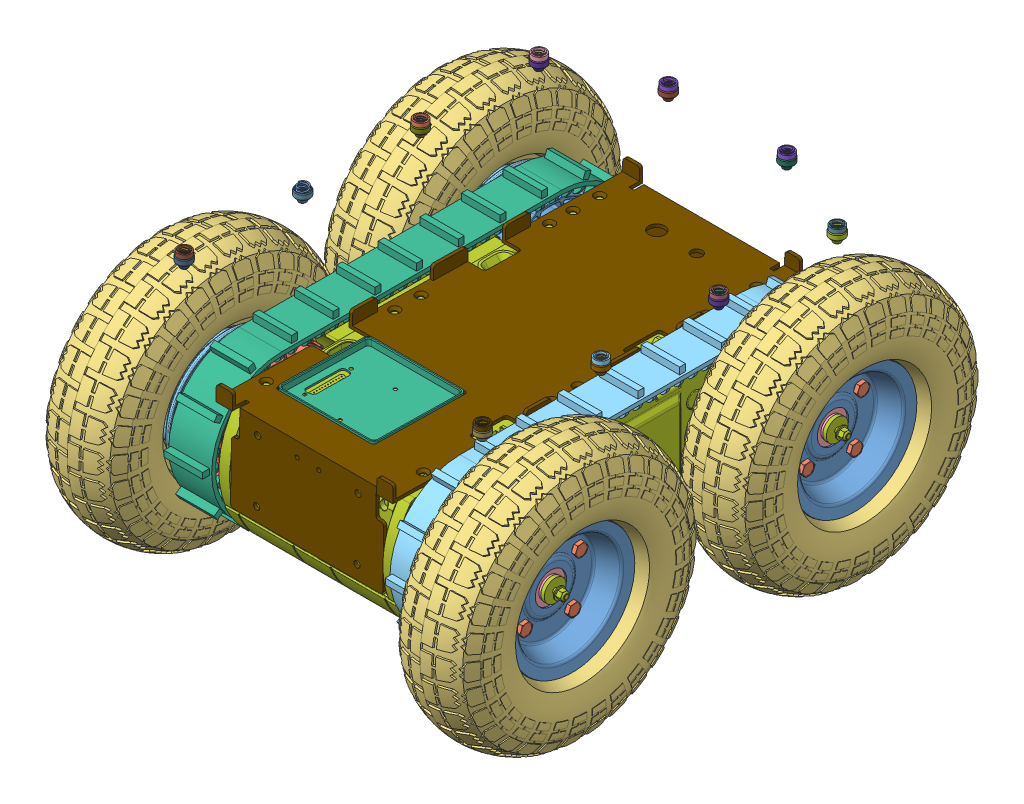
SolidWorks assembly RD_Payload_Rev_A, configuration Default. Lengths in mm.
Overall size (444.69 367.29 650.79).
94 component instances, 59 part files, 0 mates.
Components (placement in the parent):
- RD_Payload_Rev_A.step-1: RD_Payload_Rev_A.step [Default] at origin size (444.69 371.55 650.79)
  - 10 in Wheel.step-1: 10 in Wheel.step [Default] at (178.555 0 0) x (0 -0.59872 0.800958) z (-1 0 0) size (260.79 263.33 83.58)
    - Hub Outer.step-1: Hub Outer.step [Default] x (1 0 0) z (0 0 -1) size (127 127 25.4)
    - Bolt M8x14mm.step-1: Bolt M8x14mm.step [Default] at (0 34.925 -7.0104) x (1 0 0) z (0 -1 0) size (11.71 18.58 13.52)
    - Bolt M8x14mm.step-2: Bolt M8x14mm.step [Default] at (-34.925 0 -7.0104) x (1 0 0) z (0 -1 0) size (11.71 18.58 13.52)
    - Bolt M8x14mm.step-3: Bolt M8x14mm.step [Default] at (0 -34.925 -7.0104) x (1 0 0) z (0 -1 0) size (11.71 18.58 13.52)
    - Bolt M8x14mm.step-4: Bolt M8x14mm.step [Default] at (34.925 0 -7.0104) x (1 0 0) z (0 -1 0) size (11.71 18.58 13.52)
    - Tire.step-1: Tire.step [Default] x (0 0 -1) z (-0.99993 -0.011854 0) size (83.58 260.3 257.72)
    - Bearing.step-1: Bearing.step [Default] at (0 0 -2.159) x (0.59872 -0.800958 0) z (0 0 -1) size (37.59 37.59 12.4)
    - ModifiedWheelHub.step-1: ModifiedWheelHub.step [Default] at (-0.127 0 22.847) x (0 0 -1) z (1 0 0) size (30.5 125 125)
  - 10 in Wheel_1.step-1: 10 in Wheel_1.step [Default] at (180.555 0 -283.5) x (0 -0.59872 0.800958) z (-1 0 0) size (260.79 263.33 83.58)
    - Hub Outer.step-1: Hub Outer.step [Default] x (1 0 0) z (0 0 -1) size (127 127 25.4)
    - Bolt M8x14mm.step-1: Bolt M8x14mm.step [Default] at (0 34.925 -7.0104) x (1 0 0) z (0 -1 0) size (11.71 18.58 13.52)
    - Bolt M8x14mm.step-2: Bolt M8x14mm.step [Default] at (-34.925 0 -7.0104) x (1 0 0) z (0 -1 0) size (11.71 18.58 13.52)
    - Bolt M8x14mm.step-3: Bolt M8x14mm.step [Default] at (0 -34.925 -7.0104) x (1 0 0) z (0 -1 0) size (11.71 18.58 13.52)
    - Bolt M8x14mm.step-4: Bolt M8x14mm.step [Default] at (34.925 0 -7.0104) x (1 0 0) z (0 -1 0) size (11.71 18.58 13.52)
    - Tire.step-1: Tire.step [Default] x (0 0 -1) z (-0.99993 -0.011854 0) size (83.58 260.3 257.72)
    - Bearing.step-1: Bearing.step [Default] at (0 0 -2.159) x (0.59872 -0.800958 0) z (0 0 -1) size (37.59 37.59 12.4)
    - ModifiedWheelHub.step-1: ModifiedWheelHub.step [Default] at (-0.127 0 22.847) x (0 0 -1) z (1 0 0) size (30.5 125 125)
  - 10 in Wheel_2.step-1: 10 in Wheel_2.step [Default] at (-180.555 0 -283.5) x (0 -0.800958 0.59872) z (1 0 0) size (260.79 263.33 83.58)
    - Hub Outer.step-1: Hub Outer.step [Default] x (1 0 0) z (0 0 -1) size (127 127 25.4)
    - Bolt M8x14mm.step-1: Bolt M8x14mm.step [Default] at (0 34.925 -7.0104) x (1 0 0) z (0 -1 0) size (11.71 18.58 13.52)
    - Bolt M8x14mm.step-2: Bolt M8x14mm.step [Default] at (-34.925 0 -7.0104) x (1 0 0) z (0 -1 0) size (11.71 18.58 13.52)
    - Bolt M8x14mm.step-3: Bolt M8x14mm.step [Default] at (0 -34.925 -7.0104) x (1 0 0) z (0 -1 0) size (11.71 18.58 13.52)
    - Bolt M8x14mm.step-4: Bolt M8x14mm.step [Default] at (34.925 0 -7.0104) x (1 0 0) z (0 -1 0) size (11.71 18.58 13.52)
    - Tire.step-1: Tire.step [Default] x (0 0 -1) z (-0.99993 -0.011854 0) size (83.58 260.3 257.72)
    - Bearing.step-1: Bearing.step [Default] at (0 0 -2.159) x (0.59872 -0.800958 0) z (0 0 -1) size (37.59 37.59 12.4)
    - ModifiedWheelHub.step-1: ModifiedWheelHub.step [Default] at (-0.127 0 22.847) x (0 0 -1) z (1 0 0) size (30.5 125 125)
  - 10 in Wheel_3.step-1: 10 in Wheel_3.step [Default] at (-178.555 0 0) x (0 -0.800958 0.59872) z (1 0 0) size (260.79 263.33 83.58)
    - Hub Outer.step-1: Hub Outer.step [Default] x (1 0 0) z (0 0 -1) size (127 127 25.4)
    - Bolt M8x14mm.step-1: Bolt M8x14mm.step [Default] at (0 34.925 -7.0104) x (1 0 0) z (0 -1 0) size (11.71 18.58 13.52)
    - Bolt M8x14mm.step-2: Bolt M8x14mm.step [Default] at (-34.925 0 -7.0104) x (1 0 0) z (0 -1 0) size (11.71 18.58 13.52)
    - Bolt M8x14mm.step-3: Bolt M8x14mm.step [Default] at (0 -34.925 -7.0104) x (1 0 0) z (0 -1 0) size (11.71 18.58 13.52)
    - Bolt M8x14mm.step-4: Bolt M8x14mm.step [Default] at (34.925 0 -7.0104) x (1 0 0) z (0 -1 0) size (11.71 18.58 13.52)
    - Tire.step-1: Tire.step [Default] x (0 0 -1) z (-0.99993 -0.011854 0) size (83.58 260.3 257.72)
    - Bearing.step-1: Bearing.step [Default] at (0 0 -2.159) x (0.59872 -0.800958 0) z (0 0 -1) size (37.59 37.59 12.4)
    - ModifiedWheelHub.step-1: ModifiedWheelHub.step [Default] at (-0.127 0 22.847) x (0 0 -1) z (1 0 0) size (30.5 125 125)
  - R&D Payload.step-1: R&D Payload.step [Default] at (7.0458 -116.5686 -486.2193) x (1 0 0) z (0 0.999848 -0.017452) size (435.85 572.37 235.56)
    - R&D Payload Assembly (approx, don't use) v9.step-1: R&D Payload Assembly (approx, don't use) v9.step [Default] at (0 0 150) size (435.85 572.37 129.48)
      - PPatrol Payload v6.step-1: PPatrol Payload v6.step [Default] at (200.9785 -625.114 143.2331) x (0 -1 0) z (-1 0 0) size (572.37 31.75 435.85)
        - 8020-1010-BLACK-1010-BLACK X 72 v1.step-1: 8020-1010-BLACK-1010-BLACK X 72 v1.step [Default] at (-12.6721 -12.7 413.3053) size (25.4 25.4 387.35) (hidden)
        - 8020-1010-BLACK-1010-BLACK X 72 v1 (1).step-1: 8020-1010-BLACK-1010-BLACK X 72 v1 (1).step [Default] at (-25.3721 -12.7 400.6053) x (0 0 -1) z (1 0 0) size (25.4 25.4 523.88) (hidden)
        - 8020-1010-BLACK-1010-BLACK X 72 v1 (2).step-1: 8020-1010-BLACK-1010-BLACK X 72 v1 (2).step [Default] at (-536.5471 -12.7 387.9053) size (25.4 25.4 387.35) (hidden)
        - 8020-1010-BLACK-1010-BLACK X 72 v1 (1) (1).step-1: 8020-1010-BLACK-1010-BLACK X 72 v1 (1) (1).step [Default] at (-637.3851 -12.7 -418.5447) x (0 0 1) z (-1 0 0) size (25.4 25.4 523.88) (hidden)
        - Polycarbonate.step-1: Polycarbonate.step [Default] at origin size (572.37 6.4 435.85) (hidden)
      - Gasket (approximate).step-1: Gasket (approximate).step [Default] at (-17.1019 -288.0369 37.8723) x (1 0 0) z (0 -1 0) size (325.94 3 463.22) (hidden)
      - Component8.step-1: Component8.step [Default] at (-17.1019 -288.0369 37.8723) x (1 0 0) z (0 -1 0) size (99.02 8.47 93.56)
      - Component9.step-1: Component9.step [Default] at (-17.1019 -288.0369 37.8723) x (1 0 0) z (0 -1 0) size (13.43 10.76 13.43) (hidden)
      - Component10.step-1: Component10.step [Default] at (-17.1019 -288.0369 37.8723) x (1 0 0) z (0 -1 0) size (10.99 7.47 11.04)
      - Component11.step-1: Component11.step [Default] at (-17.1019 -288.0369 37.8723) x (1 0 0) z (0 -1 0) size (10.99 7.47 11.04) (hidden)
      - Component12.step-1: Component12.step [Default] at (-17.1019 -288.0369 37.8723) x (1 0 0) z (0 -1 0) size (325.94 88.29 30) (hidden)
      - Component13.step-1: Component13.step [Default] at (-17.1019 -288.0369 37.8723) x (1 0 0) z (0 -1 0) size (13.43 10.76 13.43)
      - Component14.step-1: Component14.step [Default] at (-17.1019 -288.0369 37.8723) x (1 0 0) z (0 -1 0) size (10.99 7.47 11.04)
      - Component15.step-1: Component15.step [Default] at (-17.1019 -288.0369 37.8723) x (1 0 0) z (0 -1 0) size (14.52 10.94 14.52)
      - Component16.step-1: Component16.step [Default] at (-17.1019 -288.0369 37.8723) x (1 0 0) z (0 -1 0) size (13.43 10.76 13.43)
      - Component17.step-1: Component17.step [Default] at (-17.1019 -288.0369 37.8723) x (1 0 0) z (0 -1 0) size (10.99 7.47 11.04) (hidden)
      - Component18.step-1: Component18.step [Default] at (-17.1019 -288.0369 37.8723) x (1 0 0) z (0 -1 0) size (14.52 10.94 14.52) (hidden)
      - Component19.step-1: Component19.step [Default] at (-17.1019 -288.0369 37.8723) x (1 0 0) z (0 -1 0) size (13.43 10.76 13.43) (hidden)
      - Component20.step-1: Component20.step [Default] at (-17.1019 -288.0369 37.8723) x (1 0 0) z (0 -1 0) size (10.99 7.47 11.04)
      - Component21.step-1: Component21.step [Default] at (-17.1019 -288.0369 37.8723) x (1 0 0) z (0 -1 0) size (10.99 7.47 11.04)
      - Component22.step-1: Component22.step [Default] at (-17.1019 -288.0369 37.8723) x (1 0 0) z (0 -1 0) size (14.52 10.94 14.52) (hidden)
      - Component23.step-1: Component23.step [Default] at (-17.1019 -288.0369 37.8723) x (1 0 0) z (0 -1 0) size (14.52 10.94 14.52)
      - Component24.step-1: Component24.step [Default] at (-17.1019 -288.0369 37.8723) x (1 0 0) z (0 -1 0) size (10.99 7.47 11.04)
      - Component25.step-1: Component25.step [Default] at (-17.1019 -288.0369 37.8723) x (1 0 0) z (0 -1 0) size (13.43 10.76 13.43) (hidden)
      - Component26.step-1: Component26.step [Default] at (-17.1019 -288.0369 37.8723) x (1 0 0) z (0 -1 0) size (14.52 10.94 14.52)
      - Component27.step-1: Component27.step [Default] at (-17.1019 -288.0369 37.8723) x (1 0 0) z (0 -1 0) size (14.52 10.94 14.52)
      - Component28.step-1: Component28.step [Default] at (-17.1019 -288.0369 37.8723) x (1 0 0) z (0 -1 0) size (13.43 10.76 13.43)
      - Component29.step-1: Component29.step [Default] at (-17.1019 -288.0369 37.8723) x (1 0 0) z (0 -1 0) size (10.99 7.47 11.04)
      - Component30.step-1: Component30.step [Default] at (-17.1019 -288.0369 37.8723) x (1 0 0) z (0 -1 0) size (13.43 10.76 13.43)
      - Component31.step-1: Component31.step [Default] at (-17.1019 -288.0369 37.8723) x (1 0 0) z (0 -1 0) size (10.99 7.47 11.04)
      - Component32.step-1: Component32.step [Default] at (-17.1019 -288.0369 37.8723) x (1 0 0) z (0 -1 0) size (13.43 10.76 13.43)
      - Component33.step-1: Component33.step [Default] at (-17.1019 -288.0369 37.8723) x (1 0 0) z (0 -1 0) size (13.43 10.76 13.43)
      - Component34.step-1: Component34.step [Default] at (-17.1019 -288.0369 37.8723) x (1 0 0) z (0 -1 0) size (10.99 7.47 11.04)
      - Component35.step-1: Component35.step [Default] at (-17.1019 -288.0369 37.8723) x (1 0 0) z (0 -1 0) size (325.94 88.29 403.22) (hidden)
      - Component36.step-1: Component36.step [Default] at (-17.1019 -288.0369 37.8723) x (1 0 0) z (0 -1 0) size (325.94 88.29 30) (hidden)
      - Component37.step-1: Component37.step [Default] at (-17.1019 -288.0369 37.8723) x (1 0 0) z (0 -1 0) size (14.52 10.94 14.52)
      - Component38.step-1: Component38.step [Default] at (-17.1019 -288.0369 37.8723) x (1 0 0) z (0 -1 0) size (13.43 10.76 13.43)
      - Component39.step-1: Component39.step [Default] at (-17.1019 -288.0369 37.8723) x (1 0 0) z (0 -1 0) size (14.52 10.94 14.52)
      - Component40.step-1: Component40.step [Default] at (-17.1019 -288.0369 37.8723) x (1 0 0) z (0 -1 0) size (10.99 7.47 11.04)
      - Component41.step-1: Component41.step [Default] at (-17.1019 -288.0369 37.8723) x (1 0 0) z (0 -1 0) size (14.52 10.94 14.52)
      - Component42.step-1: Component42.step [Default] at (-17.1019 -288.0369 37.8723) x (1 0 0) z (0 -1 0) size (14.52 10.94 14.52)
      - Component43.step-1: Component43.step [Default] at (-17.1019 -288.0369 37.8723) x (1 0 0) z (0 -1 0) size (13.43 10.76 13.43)
      - Component44.step-1: Component44.step [Default] at (-17.1019 -288.0369 37.8723) x (1 0 0) z (0 -1 0) size (13.43 10.76 13.43)
      - Component45.step-1: Component45.step [Default] at (-17.1019 -288.0369 37.8723) x (1 0 0) z (0 -1 0) size (14.52 10.94 14.52)
      - Component46.step-1: Component46.step [Default] at (-17.1019 -288.0369 37.8723) x (1 0 0) z (0 -1 0) size (10.99 7.47 11.04)
      - Component47.step-1: Component47.step [Default] at (-17.1019 -288.0369 37.8723) x (1 0 0) z (0 -1 0) size (14.52 10.94 14.52)
    - Rear Bracket and Payload Spacer (XXXXXX) v2.step-1: Rear Bracket and Payload Spacer (XXXXXX) v2.step [Default] at (-7.0458 -148.6279 107.7511) x (-1 0 0) z (0 1 0) size (179.03 126.19 414.77)
  - 100251_revA.step-1: 100251_revA.step [Default] at (-101.5 0 -283.5) x (0 0.000178 1) z (-1 0 0) size (137.55 138 25)
  - 100251_revA (1).step-1: 100251_revA (1).step [Default] at (-99.5 0 0) x (0 0.53745 -0.843296) z (-1 0 0) size (137.55 138 25)
  - 100251_revA (2).step-1: 100251_revA (2).step [Default] at (101.5 0 -283.5) x (0 0.53745 0.843296) z (1 0 0) size (137.55 138 25)
  - 100251_revA (3).step-1: 100251_revA (3).step [Default] at (99.5 0 0) x (0 0.000178 -1) z (1 0 0) size (137.55 138 25)
  - WODDEN_track_inner_simplified.step-1: WODDEN_track_inner_simplified.step [Default] at (112 0 -141.75) x (0 0 -1) z (1 0 0) size (439.5 156 43.5)
  - WODDEN_track_inner_simplified (1).step-1: WODDEN_track_inner_simplified (1).step [Default] at (-112 0 -141.75) x (0 0 -1) z (1 0 0) size (439.5 156 43.5)
  - 4WD_R&D_Plate_workspace.step-1: 4WD_R&D_Plate_workspace.step [Default] at origin size (400.01 131.58 418.13)
